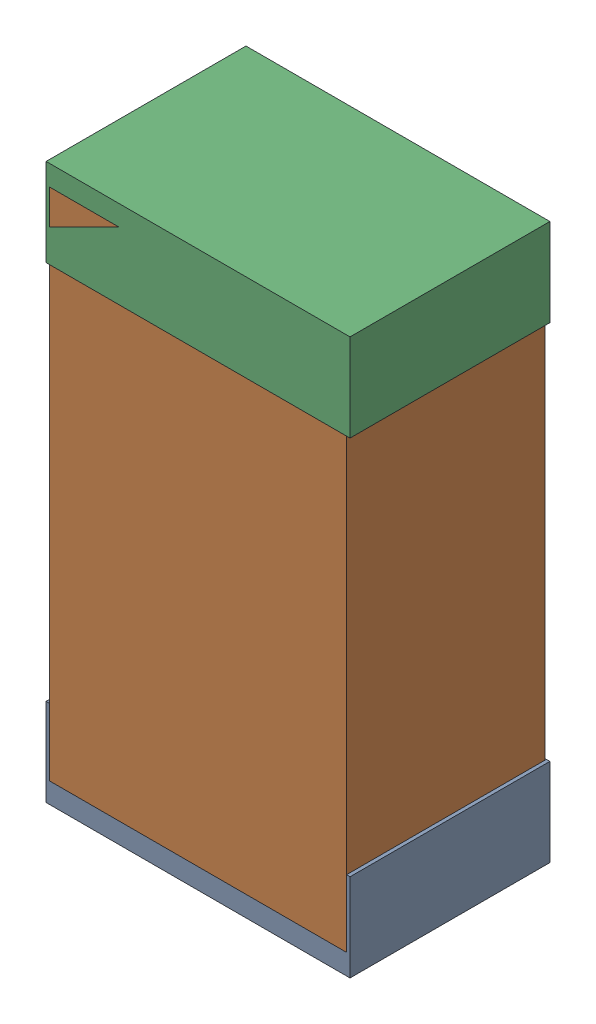
SolidWorks assembly R15Kanaloa_v2.0.0_Motor, configuration Default. Lengths in mm.
Overall size (1.3 2.38 0.85).
6 component instances, 2 part files, 0 mates.
Components (placement in the parent):
- 330415056-1: 330415056 [Default] at (87.376 65.353 -1.9574) size (1.3 0.38 0.85)
  - Extruded_2-1: Extruded_2 [Default] at origin size (1.3 0.38 0.85)
- 334787376-1: 334787376 [Default] at (87.376 66.353 -1.9524) size (1.27 2.2 0.85)
  - Extruded_16-1: Extruded_16 [Default] at origin size (1.27 2.2 0.85)
- 330415056-2: 330415056 [Default] at (87.376 67.353 -1.9574) size (1.3 0.38 0.85)
  - Extruded_2-1: Extruded_2 [Default] at origin size (1.3 0.38 0.85)
